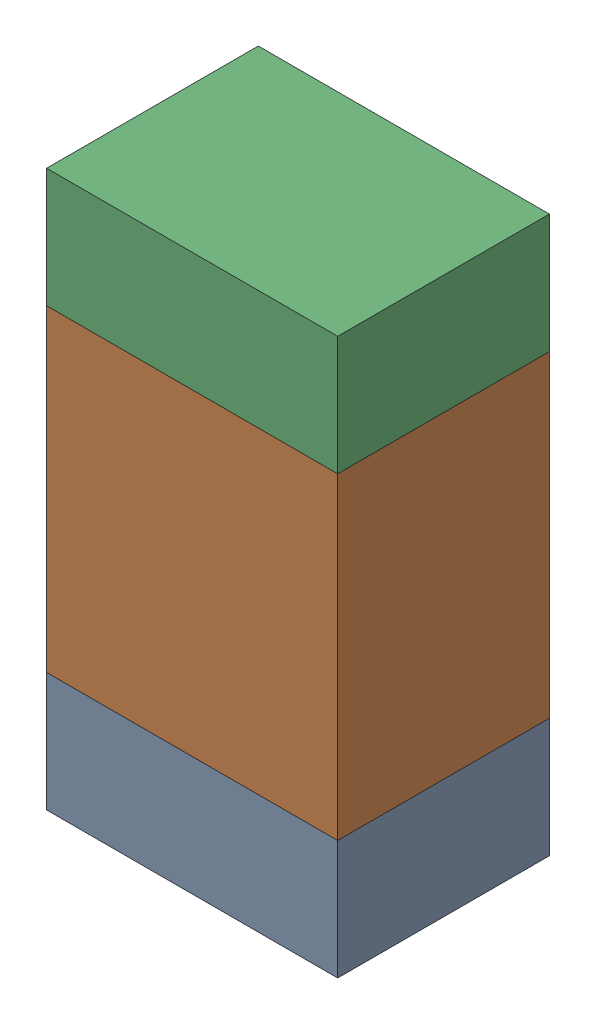
SolidWorks assembly R412PCB, configuration Default. Lengths in mm.
Overall size (0.55 1.05 0.4).
6 component instances, 2 part files, 0 mates.
Components (placement in the parent):
- 846483288-1: 846483288 [Default] at (125.4001 87.5876 -2.0638) size (0.55 0.22 0.4)
  - Extruded_12-1: Extruded_12 [Default] at origin size (0.55 0.22 0.4)
- 846483424-1: 846483424 [Default] at (125.4001 88.0001 -2.0638) size (0.55 0.6 0.4)
  - Extruded_13-1: Extruded_13 [Default] at origin size (0.55 0.6 0.4)
- 846483288-2: 846483288 [Default] at (125.4001 88.4126 -2.0638) size (0.55 0.22 0.4)
  - Extruded_12-1: Extruded_12 [Default] at origin size (0.55 0.22 0.4)
